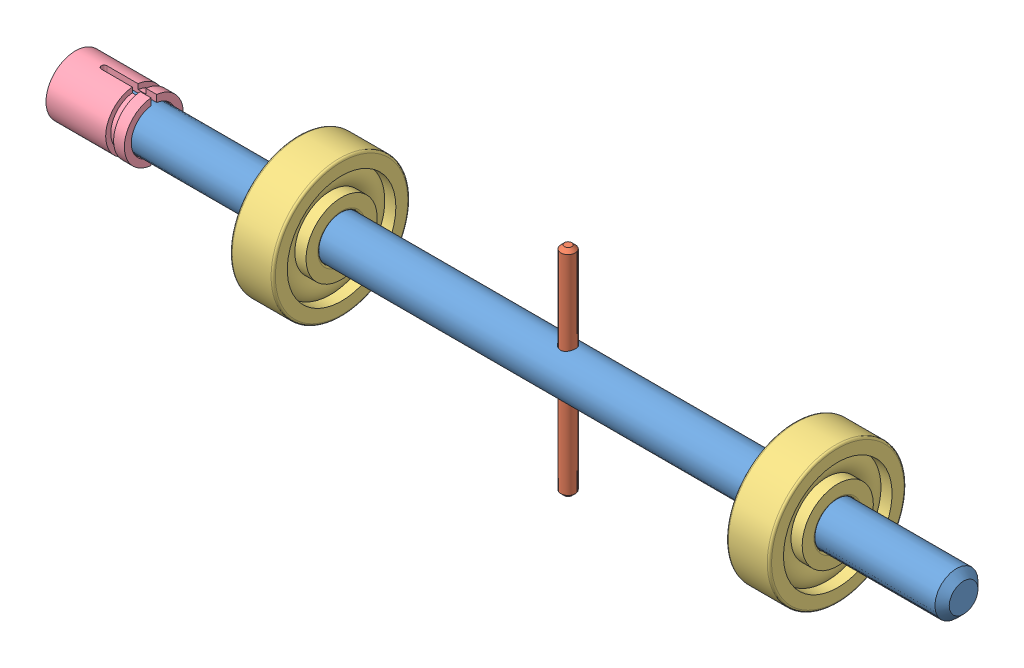
SolidWorks assembly 4.4 Shaft arm1-arm2, configuration Domyślna. Lengths in mm.
Overall size (123.6 30 19).
5 component instances, 4 part files, 15 mates.
Components (placement in the parent):
- 4.4.1 Shaft 6x120-1: 4.4.1 Shaft 6x120 [Domyślna] x (0 0 -1) z (-1 0 0) size (6 6 120)
- 4.4.2 Peg-1: 4.4.2 Peg [Domyślna] at origin size (2 30 2)
- 4.4.3 ISO 15 RBB - 026 - 8,SI,NC,8_68-3: 4.4.3 ISO 15 RBB - 026 - 8,SI,NC,8_68 [ISO 15 RBB - 026 - 8,SI,NC,8_68] at (-34.5 0 0) x (-1 0 0) z (0 0 1) size (6 19 19)
- 4.4.3 ISO 15 RBB - 026 - 8,SI,NC,8_68-2: 4.4.3 ISO 15 RBB - 026 - 8,SI,NC,8_68 [ISO 15 RBB - 026 - 8,SI,NC,8_68] at (34.5 0 0) x (-1 0 0) z (0 0 -1) size (6 19 19)
- 3.3.2 Encoder_plastic_hub-1: 3.3.2 Encoder_plastic_hub [Domyślna] at (-57.6 0 0) x (0 1 0) z (0 0 1) size (8.2 11 8.2)
Mates (geometry in assembly coordinates):
- Koncentryczne26: concentric aligned: cylinder of 4.4.1 Shaft 6x120-1 through (0 3 0) axis (0 -1 0) radius 1.05; cylinder of 4.4.2 Peg-1 through (0 15 0) axis (0 -1 0) radius 1
- Wspólnie1: coincident anti-aligned: plane of 4.4.1 Shaft 6x120-1 through (0 0 0) normal (0 -1 0); plane of 4.4.2 Peg-1 through (0 0 0) normal (0 1 0)
- Wspólnie2: coincident anti-aligned: plane of 4.4.1 Shaft 6x120-1 through (0 0 0) normal (-1 0 0); plane of assembly through (0 0 0) normal (1 0 0)
- Wspólnie3: coincident anti-aligned: plane of 4.4.1 Shaft 6x120-1 through (0 0 0) normal (0 -1 0); plane of assembly through (0 0 0) normal (0 1 0)
- Wspólnie5: coincident anti-aligned: plane of 4.4.1 Shaft 6x120-1 through (0 0 0) normal (0 0 -1); plane of assembly through (0 0 0) normal (0 0 1)
- Koncentryczne27: concentric anti-aligned: cylinder of 4.4.1 Shaft 6x120-1 through (-65 0 0) axis (1 0 0) radius 3; cylinder of 4.4.3 ISO 15 RBB - 026 - 8,SI,NC,8_68-2 through (55.1375 0 0) axis (-1 0 0) radius 9.5
- Koncentryczne28: concentric anti-aligned: cylinder of 4.4.1 Shaft 6x120-1 through (-65 0 0) axis (1 0 0) radius 3; cylinder of 4.4.3 ISO 15 RBB - 026 - 8,SI,NC,8_68-3 through (-13.8625 0 0) axis (-1 0 0) radius 9.5
- Odległość1: distance = 75 mm anti-aligned: plane of 4.4.3 ISO 15 RBB - 026 - 8,SI,NC,8_68-3 through (-37.5 -9.2 0) normal (-1 0 0); plane of 4.4.3 ISO 15 RBB - 026 - 8,SI,NC,8_68-2 through (37.5 7.55 0) normal (1 0 0)
- Wspólnie7: coincident anti-aligned: plane of 4.4.3 ISO 15 RBB - 026 - 8,SI,NC,8_68-3 through (-34.5 0 0) normal (0 -1 0); plane of assembly through (0 0 0) normal (0 1 0)
- Wspólnie8: coincident aligned: plane of 4.4.3 ISO 15 RBB - 026 - 8,SI,NC,8_68-2 through (34.5 0 0) normal (0 1 0); plane of assembly through (0 0 0) normal (0 1 0)
- Wspólnie9: coincident aligned: plane of 4.4.2 Peg-1 through (0 0 0) normal (1 0 0); plane of assembly through (0 0 0) normal (1 0 0)
- Koncentryczne29: concentric anti-aligned: cylinder of 4.4.1 Shaft 6x120-1 through (-65 0 0) axis (1 0 0) radius 3; cylinder of 3.3.2 Encoder_plastic_hub-1 through (-57.6 0 0) axis (-1 0 0) radius 4.1
- Wspólnie10: coincident aligned: plane of 3.3.2 Encoder_plastic_hub-1 through (-57.6 0 0) normal (0 0 1); plane of assembly through (0 0 0) normal (0 0 1)
- Wspólnie11: coincident anti-aligned: plane of 4.4.1 Shaft 6x120-1 through (-65 0 0) normal (-1 0 0); plane of 3.3.2 Encoder_plastic_hub-1 through (-65 0 2.85) normal (1 0 0)
- Symetrycznie1: symmetric aligned: plane of 4.4.3 ISO 15 RBB - 026 - 8,SI,NC,8_68-3 through (-31.5 -7.55 0) normal (1 0 0); plane of 4.4.3 ISO 15 RBB - 026 - 8,SI,NC,8_68-2 through (31.5 9.2 0) normal (-1 0 0); plane of assembly through (0 0 0) normal (1 0 0)
